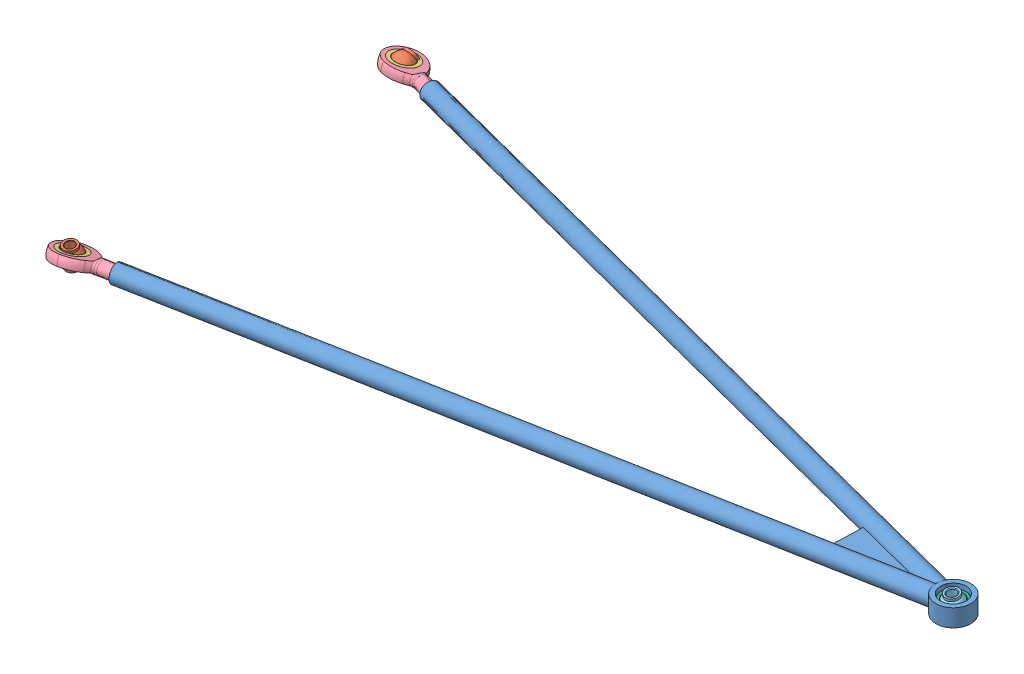
SolidWorks assembly Rear Bottom Wishbone, configuration Default. Lengths in mm.
Overall size (572.03 73.08 306.55).
12 component instances, 6 part files, 6 mates.
Components (placement in the parent):
- Rear Bottom Wishbone-1: Rear Bottom Wishbone [Default<As Machined>] at (301.5787 237.5387 460.7629) size (527.56 13.56 241.59)
- HXAM-4T Rod End-1: HXAM-4T Rod End [Default] at (-238.6096 237.5387 562.3635) x (0.866109 -0.086108 0.492382) z (-0.499708 -0.125251 0.857091) size (70.98 36.69 68.32) (flexible)
  - HXAM-4T Ball-1: HXAM-4T Ball [Default] at (0 0 -49.2252) size (15.06 15.06 15.06)
  - HXAM-4T Sleeve-1: HXAM-4T Sleeve [Default] at (37.4196 -0.7917 -31.9729) x (-0.583888 -0.455396 -0.672078) z (-0.760171 0.016083 0.649524) size (19.53 6.73 19.53)
  - HXAM-4T Housing-1: HXAM-4T Housing [Default] at (37.4196 -0.7917 -31.9729) x (-0.583888 -0.455396 -0.672078) z (-0.760171 0.016083 0.649524) size (27.48 26.04 62.51)
- HXAM-4T Rod End-2: HXAM-4T Rod End [Default] at (-238.6096 237.5387 321.0635) x (0.97958 -0.180101 -0.089373) z (0.200691 0.849087 0.488645) size (70.52 49.89 55.41) (flexible)
  - HXAM-4T Ball-1: HXAM-4T Ball [Default] at (0 0 -49.2252) size (15.06 15.06 15.06)
  - HXAM-4T Sleeve-1: HXAM-4T Sleeve [Default] at (45.5826 -10.119 15.5868) x (-0.363586 -0.711373 0.601459) z (-0.926002 0.205565 -0.316643) size (19.53 6.73 19.53)
  - HXAM-4T Housing-1: HXAM-4T Housing [Default] at (45.5826 -10.119 15.5868) x (-0.363586 -0.711373 0.601459) z (-0.926002 0.205565 -0.316643) size (27.48 26.04 62.51)
- HAB-4T Bearing-1: HAB-4T Bearing [Default] at (301.5787 237.5387 460.7629) x (0.999229 0.002177 -0.039188) z (0.039099 -0.142052 0.989087) size (18.92 15.06 19.64) (flexible)
  - HAB-4T Ball-1: HAB-4T Ball [Default] at origin size (15.06 15.06 15.06)
  - HAB-4T Cup-1: HAB-4T Cup [Default] x (0.999979 -0.001295 0.006305) z (-0.006057 0.142063 0.989839) size (18.8 6.48 18.8)
Mates (geometry in assembly coordinates):
- Concentric1: concentric anti-aligned: cylinder of Rear Bottom Wishbone-1 through (301.5787 244.3164 460.7629) axis (0 -1 0) radius 9.3345; cylinder of HAB-4T Bearing-1/HAB-4T Cup-1 through (301.5787 237.5387 460.7629) axis (0 1 0) radius 9.398
- Coincident1: coincident anti-aligned: plane of Rear Bottom Wishbone-1 through (301.5787 234.3002 460.7629) normal (0 1 0); plane of HAB-4T Bearing-1/HAB-4T Cup-1 through (301.5787 234.3002 460.7629) normal (0 -1 0)
- Concentric2: concentric aligned: cylinder of Rear Bottom Wishbone-1 through (-211.6948 237.5387 328.024) axis (0.968149 0 0.250375) radius 6.35; cylinder of HXAM-4T Rod End-2/HXAM-4T Housing-1 through (-205.8532 237.5387 329.5347) axis (0.968149 0 0.250375) radius 4.7625
- Concentric3: concentric anti-aligned: cylinder of Rear Bottom Wishbone-1 through (301.5787 237.5387 460.7629) axis (-0.982768 0 0.184843) radius 6.35; cylinder of ? through (-205.3586 237.5387 556.1095) axis (0.982768 0 -0.184843) radius 4.7625
- Coincident2: coincident: point of Rear Bottom Wishbone-1; point of HXAM-4T Rod End-1/HXAM-4T Ball-1
- Coincident3: coincident: point of Rear Bottom Wishbone-1; point of HXAM-4T Rod End-2/HXAM-4T Ball-1
